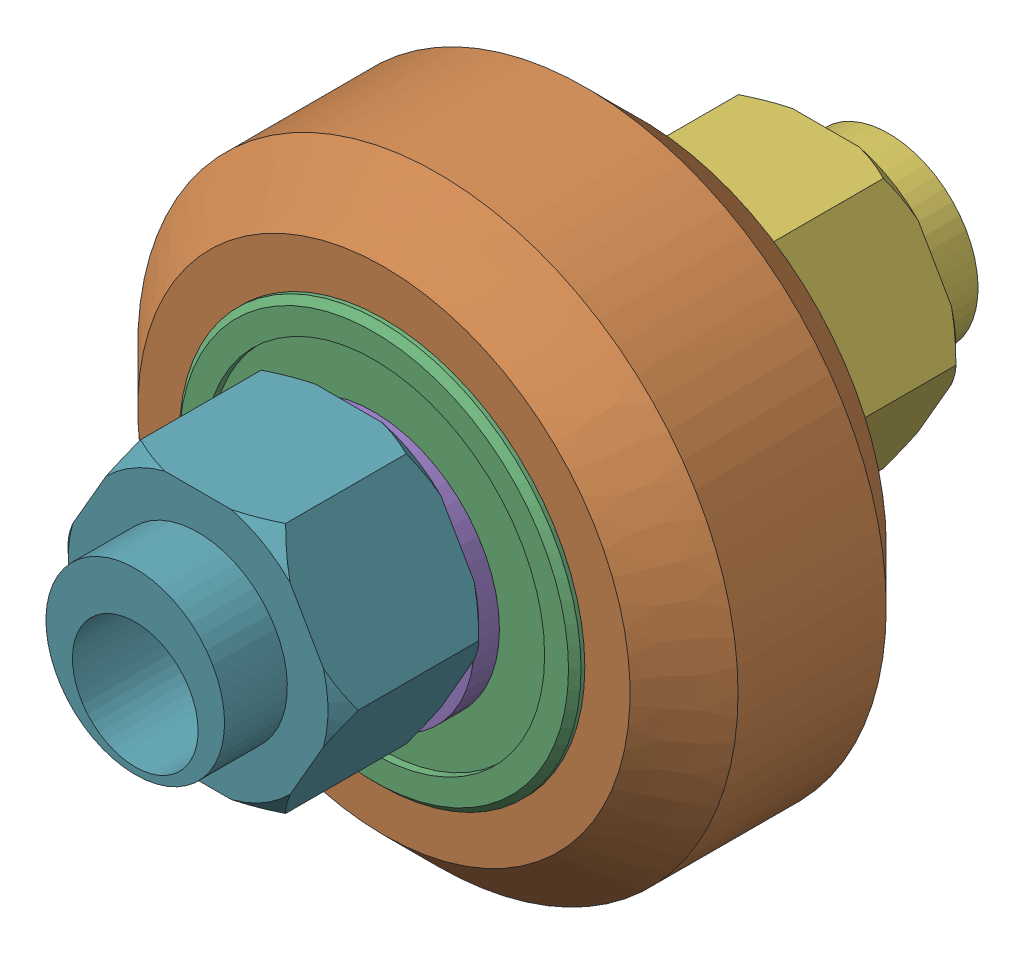
SolidWorks assembly Outboard Wheel Stack_1, configuration Default. Lengths in mm.
Overall size (23.9 23.9 30).
9 component instances, 4 part files, 0 mates.
Components (placement in the parent):
- Xtreme Solid V Wheel Kit Assembly_5-1: Xtreme Solid V Wheel Kit Assembly_5 [Default] at origin size (23.9 23.9 13)
  - Precision Shim - 10x5x1mm-1: Precision Shim - 10x5x1mm [Default] at origin size (10 10 1)
  - Xtreme Solid V Wheel Assembly_5-1: Xtreme Solid V Wheel Assembly_5 [Default] at (84.85 55.79 -23.5) size (23.9 23.9 11)
    - Xtreme Solid V Wheel-1: Xtreme Solid V Wheel [Default] at (-84.85 -55.79 30) x (0 0 1) z (-1 0 0) size (10.2 23.9 23.9)
    - Wheel+Kit+-+5x16x5mm+Sealed+Radial+Ball+Bearing.step.f3d-1: Wheel+Kit+-+5x16x5mm+Sealed+Radial+Ball+Bearing.step.f3d [Default] at (-84.85 -55.79 30) x (0 1 0) z (-1 0 0) size (16 5 16)
    - Wheel+Kit+-+5x16x5mm+Sealed+Radial+Ball+Bearing.step.f3d-2: Wheel+Kit+-+5x16x5mm+Sealed+Radial+Ball+Bearing.step.f3d [Default] at (-84.85 -55.79 30) x (0 1 0) z (1 0 0) size (16 5 16)
  - Precision Shim - 10x5x1mm-2: Precision Shim - 10x5x1mm [Default] at (0 0 12) size (10 10 1)
- Eccentric Spacer 6mm-1: Eccentric Spacer 6mm [Default] at (0 0.79 -6) x (1 0 0) z (0 -1 0) size (11.55 8.5 10)
- Eccentric Spacer 6mm-2: Eccentric Spacer 6mm [Default] at (0 0.79 19) x (-1 0 0) z (0 -1 0) size (11.55 8.5 10)
